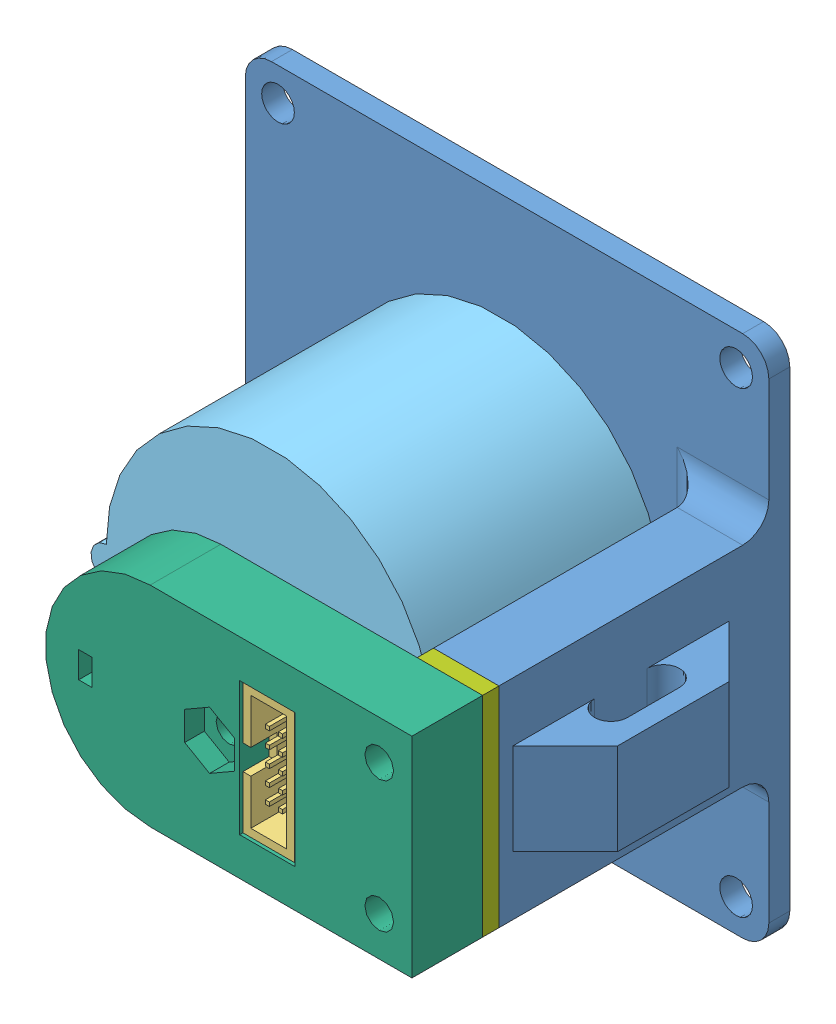
SolidWorks assembly F22-SF-0007, configuration Default. Lengths in mm.
Overall size (55.88 50.8 36.66).
7 component instances, 7 part files, 16 mates.
Components (placement in the parent):
- F22-SF-3013-1: F22-SF-3013 [Default] at (-16.1552 2.2955 42.2999) size (55.88 50.8 28.22)
- Bearing_R4-2Z_0p25x0p625x0.196_MC_60355K430-1: Bearing_R4-2Z_0p25x0p625x0.196_MC_60355K430 [60355K43] at (9.2448 27.6955 46.8211) x (0.998203 0.059919 0) z (0 0 1) size (15.88 15.88 4.98)
- SRX_Mag_Encoder_PCB_CTRE_15-697867-1: SRX_Mag_Encoder_PCB_CTRE_15-697867 [Default] at (15.0106 27.6955 73.6943) x (0 -1 0) z (0 0 -1) size (16.08 23.32 8.57)
- F22-SF-7001-1: F22-SF-7001 [Default] at (9.2448 27.6955 54.6443) x (-0.502269 -0.864712 0) z (0 0 1) size (6.35 6.35 12.7)
- F22-SF-3014-1: F22-SF-3014 [Default] at (9.2448 27.6955 45.1193) x (0.993928 0.110031 0) z (0 0 1) size (33.26 31.75 23.5)
- F22-SF-3015-1: F22-SF-3015 [Default] at (15.0106 27.6955 73.6943) x (0 -1 0) z (0 0 -1) size (20.32 35.56 6.86)
- F22-SF-3016-1: F22-SF-3016 [Default] at (34.6448 17.5355 70.5193) x (0 1 0) z (0 0 1) size (20.32 6.35 1.59)
Mates (geometry in assembly coordinates):
- Concentric1: concentric anti-aligned: cylinder of F22-SF-3013-1 through (9.2448 27.6955 48.1419) axis (0 0 -1) radius 8.001; cylinder of Bearing_R4-2Z_0p25x0p625x0.196_MC_60355K430-1 through (9.2448 27.6955 49.3103) axis (0 0 1) radius 7.9375
- Coincident1: coincident anti-aligned: plane of F22-SF-3013-1 through (9.2448 27.6955 44.3319) normal (0 0 1); plane of Bearing_R4-2Z_0p25x0p625x0.196_MC_60355K430-1 through (8.7841 35.3702 44.3319) normal (0 0 -1)
- Concentric2: concentric anti-aligned: cylinder of F22-SF-7001-1 through (9.2448 27.6955 67.3443) axis (0 0 -1) radius 3.175; cylinder of F22-SF-3014-1 through (9.2448 27.6955 54.6443) axis (0 0 1) radius 3.2703
- Coincident2: coincident anti-aligned: plane of F22-SF-7001-1 through (9.2448 27.6955 54.6443) normal (0 0 -1); plane of F22-SF-3014-1 through (9.2448 27.6955 54.6443) normal (0 0 1)
- Concentric3: concentric aligned: cylinder of F22-SF-3013-1 through (9.2448 27.6955 48.1419) axis (0 0 -1) radius 10.541; cylinder of F22-SF-3014-1 through (9.2448 27.6955 50.1993) axis (0 0 -1) radius 10.795
- Coincident3: coincident anti-aligned: plane of Bearing_R4-2Z_0p25x0p625x0.196_MC_60355K430-1 through (8.9406 32.7636 49.3103) normal (0 0 1); plane of F22-SF-3014-1 through (9.2448 27.6955 49.3103) normal (0 0 -1)
- Concentric4: concentric anti-aligned: cylinder of SRX_Mag_Encoder_PCB_CTRE_15-697867-1 through (9.2448 27.6955 74.3854) axis (0 0 1) radius 8.1978; cylinder of F22-SF-3014-1 through (9.2448 27.6955 67.3443) axis (0 0 -1) radius 15.875
- Concentric5: concentric anti-aligned: cylinder of SRX_Mag_Encoder_PCB_CTRE_15-697867-1 through (15.0106 27.6955 74.3854) axis (0 0 1) radius 1.27; cylinder of F22-SF-3015-1 through (15.0106 27.6955 81.2434) axis (0 0 -1) radius 1.27
- Parallel1: parallel anti-aligned: plane of SRX_Mag_Encoder_PCB_CTRE_15-697867-1 through (23.06 34.0455 81.0529) normal (1 0 0); plane of F22-SF-3015-1 through (23.314 34.1725 123.2061) normal (-1 0 0)
- Coincident5: coincident anti-aligned: plane of SRX_Mag_Encoder_PCB_CTRE_15-697867-1 through (9.2448 27.6955 75.9729) normal (0 0 1); plane of F22-SF-3015-1 through (15.0106 27.6955 75.9729) normal (0 0 -1)
- Concentric6: concentric aligned: cylinder of F22-SF-3013-1 through (31.4698 21.3455 51.4693) axis (0 0 1) radius 0.9525; cylinder of F22-SF-3015-1 through (31.4698 21.3455 74.3854) axis (0 0 1) radius 1.397
- Concentric7: concentric aligned: cylinder of F22-SF-3013-1 through (31.4698 34.0455 51.4693) axis (0 0 1) radius 0.9525; cylinder of F22-SF-3015-1 through (31.4698 34.0455 74.3854) axis (0 0 1) radius 1.397
- Coincident6: coincident anti-aligned: plane of F22-SF-3013-1 through (-16.1552 2.2955 70.5193) normal (0 0 1); plane of F22-SF-3016-1 through (34.6448 17.5355 70.5193) normal (0 0 -1)
- Concentric8: concentric anti-aligned: cylinder of F22-SF-3013-1 through (31.4698 21.3455 67.9793) axis (0 0 1) radius 1.143; cylinder of F22-SF-3016-1 through (31.4698 21.3455 72.1068) axis (0 0 -1) radius 1.5875
- Concentric9: concentric anti-aligned: cylinder of F22-SF-3013-1 through (31.4698 34.0455 67.9793) axis (0 0 1) radius 1.143; cylinder of F22-SF-3016-1 through (31.4698 34.0455 72.1068) axis (0 0 -1) radius 1.5875
- Coincident7: coincident anti-aligned: plane of F22-SF-3015-1 through (9.2448 27.6955 72.1068) normal (0 0 -1); plane of F22-SF-3016-1 through (34.6448 17.5355 72.1068) normal (0 0 1)
